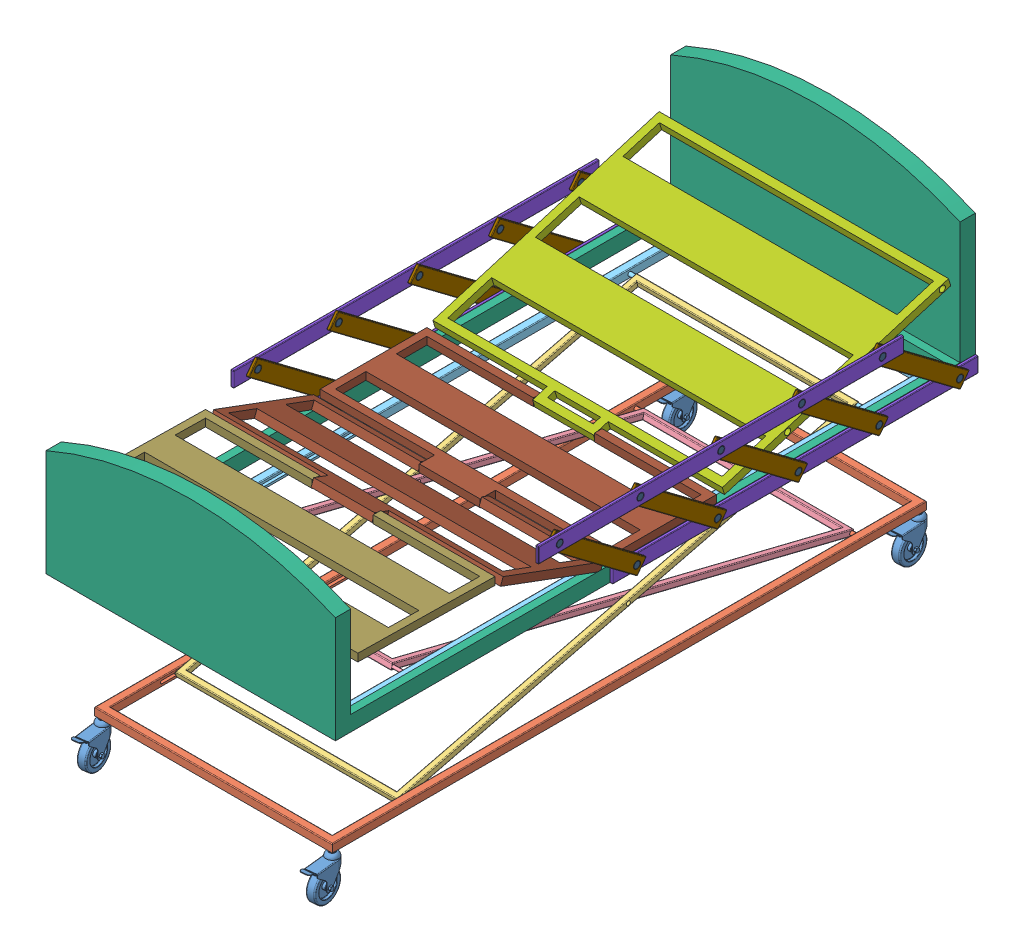
SolidWorks assembly cama hospital, configuration Predeterminado. Lengths in mm.
Overall size (1010 1083.05 2119.7).
49 component instances, 12 part files, 34 mates.
Components (placement in the parent):
- Rueda-4: Rueda [Varsayılan] at (-251.8744 22.0434 439.3813) x (-0.135874 0 -0.990726) z (0.990726 0 -0.135874) size (124.49 153.4 58.5)
- base ruedas-1: base ruedas [Predeterminado] at (120.7097 107.1934 -554.8173) size (780 26 1950)
- ajustador de altura movil-1: ajustador de altura movil [Predeterminado] at (120.7097 295.9948 -579.9511) x (1 0 0) z (0 -0.24069 0.970602) size (767 19.5 1560)
- ajustador de altura fijo-1: ajustador de altura fijo [Predeterminado] at (120.7097 295.9948 -575.2576) x (1 0 0) z (0 0.24069 0.970602) size (806 19.5 1560)
- Rueda-5: Rueda [Varsayılan] at (-254.6682 22.0434 -1484.3578) x (-0.049912 0 -0.998754) z (0.998754 0 -0.049912) size (124.49 153.4 58.5)
- Rueda-6: Rueda [Varsayılan] at (499.7087 22.0434 -1484.3788) x (-0.061507 0 -0.998107) z (0.998107 0 -0.061507) size (124.49 153.4 58.5)
- Rueda-7: Rueda [Varsayılan] at (501.161 22.0434 439.499) x (-0.106196 0 -0.994345) z (0.994345 0 -0.106196) size (124.49 153.4 58.5)
- base de altura superior-1: base de altura superior [Predeterminado] at (120.7097 480.323 -554.8173) size (819 26 1950)
- base colchón-1: base colchón [Predeterminado] at (121.2097 506.323 -554.8173) size (950 550.02 2100)
- espaldar-1: espaldar [Predeterminado] at (121.2097 682.4764 -1164.9819) x (1 0 0) z (0 -0.287147 0.957886) size (950 25 825)
- baranda-1: baranda [Predeterminado] at (994.913 612.4502 -122.1567) x (0 -1 0) z (0 0 1) size (262.27 30 1463.8)
  - eslabón baranda horizontal-1: eslabón baranda horizontal [Predeterminado] at (81.1272 -398.7033 -882.6606) size (50 10 1200)
  - eslabón baranda vertical-1: eslabón baranda vertical [Predeterminado] at (-18.0048 -388.7033 -485.7597) x (-0.799399 0 -0.6008) z (0.6008 0 -0.799399) size (50 10 370)
  - eslabón baranda vertical-2: eslabón baranda vertical [Predeterminado] at (-18.0048 -388.7033 -750.7597) x (-0.799399 0 -0.6008) z (0.6008 0 -0.799399) size (50 10 370)
  - eslabón baranda vertical-3: eslabón baranda vertical [Predeterminado] at (-18.0048 -388.7033 -1015.7597) x (-0.799399 0 -0.6008) z (0.6008 0 -0.799399) size (50 10 370)
  - eslabón baranda horizontal-2: eslabón baranda horizontal [Predeterminado] at (-117.1368 -378.7033 -618.8588) size (50 10 1200)
  - unión baranda-1: unión baranda [Predeterminado] at (-117.1368 -368.7033 -353.8588) x (0.963279 0 -0.268503) z (0 -1 0) size (20 20 20)
  - unión baranda-2: unión baranda [Predeterminado] at (-117.1368 -368.7033 -618.8588) x (1 0 0) z (0 -1 0) size (20 20 20)
  - unión baranda-3: unión baranda [Predeterminado] at (-117.1368 -368.7033 -883.8588) x (1 0 0) z (0 -1 0) size (20 20 20)
  - unión baranda-4: unión baranda [Predeterminado] at (81.1272 -378.7033 -1147.6606) x (1 0 0) z (0 -1 0) size (20 20 20)
  - unión baranda-5: unión baranda [Predeterminado] at (81.1272 -378.7033 -882.6606) x (1 0 0) z (0 -1 0) size (20 20 20)
  - unión baranda-6: unión baranda [Predeterminado] at (81.1272 -378.7033 -617.6606) x (1 0 0) z (0 -1 0) size (20 20 20)
  - unión baranda-13: unión baranda [Predeterminado] at (81.1272 -378.7033 -1412.6606) x (-0.85467 0 0.519172) z (0 -1 0) size (20 20 20)
  - unión baranda-14: unión baranda [Predeterminado] at (-117.1368 -368.7033 -1148.8588) x (1 0 0) z (0 -1 0) size (20 20 20)
  - unión baranda-15: unión baranda [Predeterminado] at (81.1272 -378.7033 -352.6606) x (1 0 0) z (0 -1 0) size (20 20 20)
  - unión baranda-16: unión baranda [Predeterminado] at (-117.1368 -368.7033 -88.8588) x (1 0 0) z (0 -1 0) size (20 20 20)
  - eslabón baranda vertical-7: eslabón baranda vertical [Predeterminado] at (-18.0048 -388.7033 -1280.7597) x (-0.799399 0 -0.6008) z (0.6008 0 -0.799399) size (50 10 370)
  - eslabón baranda vertical-8: eslabón baranda vertical [Predeterminado] at (-18.0048 -388.7033 -220.7597) x (-0.799399 0 -0.6008) z (0.6008 0 -0.799399) size (50 10 370)
- baranda-3: baranda [Predeterminado] at (14.913 648.4598 -1623.6761) x (0 1 0) z (0 0 -1) size (262.27 30 1463.8)
  - eslabón baranda horizontal-1: eslabón baranda horizontal [Predeterminado] at (81.1272 -398.7033 -882.6606) size (50 10 1200)
  - eslabón baranda vertical-1: eslabón baranda vertical [Predeterminado] at (-18.0048 -388.7033 -485.7597) x (-0.799399 0 -0.6008) z (0.6008 0 -0.799399) size (50 10 370)
  - eslabón baranda vertical-2: eslabón baranda vertical [Predeterminado] at (-18.0048 -388.7033 -750.7597) x (-0.799399 0 -0.6008) z (0.6008 0 -0.799399) size (50 10 370)
  - eslabón baranda vertical-3: eslabón baranda vertical [Predeterminado] at (-18.0048 -388.7033 -1015.7597) x (-0.799399 0 -0.6008) z (0.6008 0 -0.799399) size (50 10 370)
  - eslabón baranda horizontal-2: eslabón baranda horizontal [Predeterminado] at (-117.1368 -378.7033 -618.8588) size (50 10 1200)
  - unión baranda-1: unión baranda [Predeterminado] at (-117.1368 -368.7033 -353.8588) x (0.963279 0 -0.268503) z (0 -1 0) size (20 20 20)
  - unión baranda-2: unión baranda [Predeterminado] at (-117.1368 -368.7033 -618.8588) x (1 0 0) z (0 -1 0) size (20 20 20)
  - unión baranda-3: unión baranda [Predeterminado] at (-117.1368 -368.7033 -883.8588) x (1 0 0) z (0 -1 0) size (20 20 20)
  - unión baranda-4: unión baranda [Predeterminado] at (81.1272 -378.7033 -1147.6606) x (1 0 0) z (0 -1 0) size (20 20 20)
  - unión baranda-5: unión baranda [Predeterminado] at (81.1272 -378.7033 -882.6606) x (1 0 0) z (0 -1 0) size (20 20 20)
  - unión baranda-6: unión baranda [Predeterminado] at (81.1272 -378.7033 -617.6606) x (1 0 0) z (0 -1 0) size (20 20 20)
  - unión baranda-13: unión baranda [Predeterminado] at (81.1272 -378.7033 -1412.6606) x (-0.85467 0 0.519172) z (0 -1 0) size (20 20 20)
  - unión baranda-14: unión baranda [Predeterminado] at (-117.1368 -368.7033 -1148.8588) x (1 0 0) z (0 -1 0) size (20 20 20)
  - unión baranda-15: unión baranda [Predeterminado] at (81.1272 -378.7033 -352.6606) x (1 0 0) z (0 -1 0) size (20 20 20)
  - unión baranda-16: unión baranda [Predeterminado] at (-117.1368 -368.7033 -88.8588) x (1 0 0) z (0 -1 0) size (20 20 20)
  - eslabón baranda vertical-7: eslabón baranda vertical [Predeterminado] at (-18.0048 -388.7033 -1280.7597) x (-0.799399 0 -0.6008) z (0.6008 0 -0.799399) size (50 10 370)
  - eslabón baranda vertical-8: eslabón baranda vertical [Predeterminado] at (-18.0048 -388.7033 -220.7597) x (-0.799399 0 -0.6008) z (0.6008 0 -0.799399) size (50 10 370)
- reposa pierna-4: reposa pierna [Predeterminado] at (121.2097 556.323 -154.8173) x (-1 0 0) z (0 0 -1) size (950 25 400)
- reposa pierna-5: reposa pierna [Predeterminado] at (121.2097 761.6591 187.7744) x (-1 0 0) z (0 -0.348177 -0.937429) size (950 25 400)
- reposa pies-4: reposa pies [Predeterminado] at (121.2097 696.1472 571.8426) x (-1 0 0) z (0 -0.015755 -0.999876) size (950 25 450)
Mates (geometry in assembly coordinates):
- Concéntrica1: concentric aligned: circle of 75MM FRENLI TEKERLEK-4; circle of base ruedas-1
- Coincidente2: coincident anti-aligned: plane of 75MM FRENLI TEKERLEK-4 through (-251.8744 107.1934 439.3813) normal (0 1 0); plane of base ruedas-1 through (120.7097 107.1934 -554.8173) normal (0 -1 0)
- Concéntrica2: concentric aligned: circle of base ruedas-1; circle of 75MM FRENLI TEKERLEK-5
- Coincidente6: coincident anti-aligned: plane of base ruedas-1 through (120.7097 107.1934 -554.8173) normal (0 -1 0); plane of 75MM FRENLI TEKERLEK-5 through (-254.6682 107.1934 -1484.3578) normal (0 1 0)
- Concéntrica3: concentric aligned: circle of base ruedas-1; circle of 75MM FRENLI TEKERLEK-6
- Coincidente8: coincident anti-aligned: plane of base ruedas-1 through (120.7097 107.1934 -554.8173) normal (0 -1 0); plane of 75MM FRENLI TEKERLEK-6 through (499.7087 107.1934 -1484.3788) normal (0 1 0)
- Concéntrica4: concentric aligned: circle of base ruedas-1; circle of 75MM FRENLI TEKERLEK-7
- Coincidente10: coincident anti-aligned: plane of base ruedas-1 through (120.7097 107.1934 -554.8173) normal (0 -1 0); plane of 75MM FRENLI TEKERLEK-7 through (501.161 107.1934 439.499) normal (0 1 0)
- Ranura1: slot anti-aligned: cylinder of ajustador de altura movil-1 through (504.2097 118.8934 174.7336) axis (-1 0 0) radius 4.875; plane of base ruedas-1 through (-262.7903 114.0184 -554.8173) normal (0 1 0); cylinder of base ruedas-1 through (-262.7903 118.8934 225.1827) axis (1 0 0) radius 4.875
- Coincidente13: coincident anti-aligned: plane of base ruedas-1 through (504.2097 107.1934 -554.8173) normal (-1 0 0); plane of ajustador de altura movil-1 through (504.2097 118.8934 174.7336) normal (1 0 0)
- Concéntrica5: concentric aligned: circle of base ruedas-1; circle of ajustador de altura fijo-1
- Coincidente15: coincident anti-aligned: plane of base ruedas-1 through (465.2097 118.8934 -1329.9423) normal (-1 0 0); plane of ajustador de altura fijo-1 through (465.2097 502.6597 177.1185) normal (1 0 0)
- Concéntrica6: concentric aligned: circle of ajustador de altura movil-1; circle of ajustador de altura fijo-1
- Coincidente21: coincident anti-aligned: circle of ajustador de altura movil-1; circle of base ruedas-2
- Ranura3: slot anti-aligned: cylinder of ajustador de altura fijo-1 through (484.7097 492.023 174.7336) axis (-1 0 0) radius 4.875; plane of base de altura superior-1 through (-282.2903 487.148 -554.8173) normal (0 1 0); cylinder of base de altura superior-1 through (-282.2903 492.023 225.1827) axis (1 0 0) radius 4.875
- Distancia límite1: limit distance = 347.1296 mm anti-aligned: plane of base de altura superior-1 through (120.7097 480.323 -554.8173) normal (0 -1 0); plane of base ruedas-1 through (120.7097 133.1934 -554.8173) normal (0 1 0)
- Distancia2: distance = 65 mm aligned: plane of base colchón-1 through (-353.7903 556.323 445.1827) normal (-1 0 0); plane of base de altura superior-1 through (-288.7903 506.323 420.1827) normal (-1 0 0)
- Distancia3: distance = 75 mm aligned: plane of base colchón-1 through (121.2097 506.323 -1604.8173) normal (0 0 -1); plane of base de altura superior-1 through (-288.7903 506.323 -1529.8173) normal (0 0 -1)
- Coincidente24: coincident anti-aligned: plane of base de altura superior-1 through (120.7097 506.323 -554.8173) normal (0 1 0); plane of base colchón-1 through (121.2097 506.323 -554.8173) normal (0 -1 0)
- Coincidente34: coincident aligned: plane of base colchón-1 through (121.2097 506.323 -554.8173) normal (0 -1 0); plane of baranda-1/eslabón baranda horizontal-1 through (606.2097 506.323 -404.8173) normal (0 -1 0)
- Coincidente35: coincident aligned: plane of base colchón-1 through (121.2097 506.323 -1604.8173) normal (0 0 -1); plane of baranda-1/eslabón baranda horizontal-1 through (606.2097 556.323 -1604.8173) normal (0 0 -1)
- Coincidente36: coincident anti-aligned: plane of base colchón-1 through (596.2097 556.323 445.1827) normal (1 0 0); plane of baranda-1/eslabón baranda horizontal-1 through (596.2097 531.323 -1004.8173) normal (-1 0 0)
- Coincidente37: coincident aligned: plane of base colchón-1 through (121.2097 506.323 -554.8173) normal (0 -1 0); plane of baranda-3/eslabón baranda horizontal-2 through (-353.7903 506.323 -1604.8173) normal (0 -1 0)
- Coincidente38: coincident aligned: plane of base colchón-1 through (121.2097 506.323 -1604.8173) normal (0 0 -1); plane of baranda-3/eslabón baranda horizontal-2 through (-353.7903 506.323 -1604.8173) normal (0 0 -1)
- Coincidente39: coincident anti-aligned: plane of base colchón-1 through (-353.7903 556.323 445.1827) normal (-1 0 0); plane of baranda-3/eslabón baranda horizontal-2 through (-353.7903 531.323 -1004.8173) normal (1 0 0)
- Coincidente40: coincident anti-aligned: plane of base colchón-1 through (121.2097 556.323 -554.8173) normal (0 1 0); plane of reposa pierna-4 through (121.2097 556.323 -154.8173) normal (0 -1 0)
- Coincidente41: coincident anti-aligned: circle of espaldar-1; circle of reposa pies-2
- Ángulo límite2: limit planar angle = 0.291248 rad aligned: plane of espaldar-1 through (121.2097 706.4236 -1157.8032) normal (0 0.957886 0.287147); plane of reposa pierna-4 through (121.2097 581.323 -154.8173) normal (0 1 0)
- Coincidente42: coincident aligned: plane of base colchón-1 through (596.2097 556.323 445.1827) normal (1 0 0); plane of reposa pierna-4 through (596.2097 581.323 -754.8173) normal (1 0 0)
- Distancia4: distance = 850 mm anti-aligned: plane of reposa pierna-4 through (121.2097 556.323 -404.8173) normal (0 0 1); plane of base colchón-1 through (-353.7903 856.323 445.1827) normal (0 0 -1)
- Coincidente44: coincident anti-aligned: circle of reposa pies-2; circle of reposa pies-3
- Ángulo límite3: limit planar angle = 0.355626 rad aligned: plane of reposa pies-3 through (121.2097 785.0949 179.0699) normal (0 0.937429 -0.348177); plane of reposa pies-2 through (121.2097 581.323 -154.8173) normal (0 1 0)
- Coincidente45: coincident anti-aligned: circle of reposa pierna-5; circle of reposa pies-4
- Ángulo límite4: limit planar angle = 0.015756 rad aligned: plane of reposa pies-4 through (121.2097 721.1441 571.4487) normal (0 0.999876 -0.015755); plane of base colchón-1 through (121.2097 556.323 -554.8173) normal (0 1 0)
